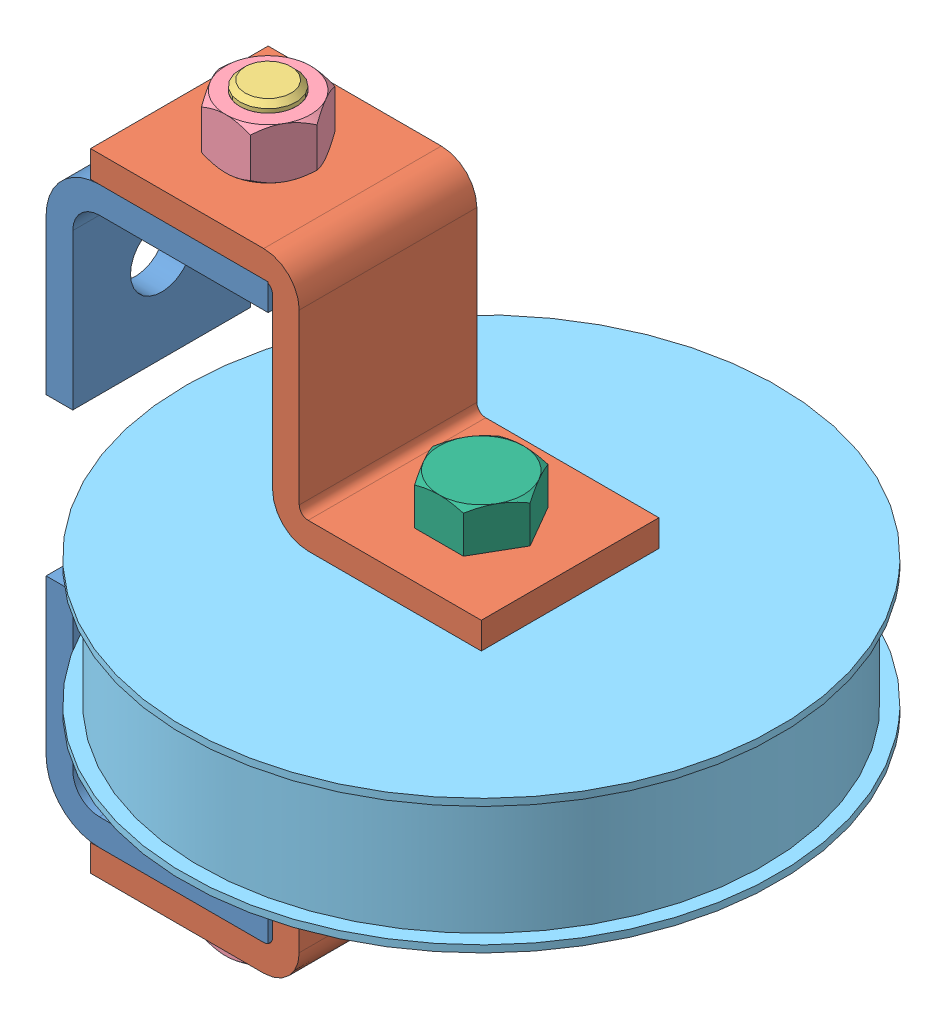
SolidWorks assembly Large Pulley Mount, configuration Default. Lengths in mm.
Overall size (187.97 168.14 187.97).
11 component instances, 6 part files, 17 mates.
Components (placement in the parent):
- P1026 - Unistrut 2-Hole 90 deg Fitting-1: P1026 - Unistrut 2-Hole 90 deg Fitting [Default] at (18.6827 -44.2712 5.2371) size (50 47 40)
- P1347 - Unistrut 2-Hole Z Fitting-1: P1347 - Unistrut 2-Hole Z Fitting [Default] at (28.6827 8.7288 -34.7629) x (1 0 0) z (0 0 -1) size (88 54 40)
- HBOLT 0.5000-13x1x1-N-1: HBOLT 0.5000-13x1x1-N [HBOLT 0.5000-13x1x1-N] at (48.6827 -12.5168 -14.7629) x (0 1 0) z (0 0 1) size (34.65 22 19.05)
- Hex Nut .5-20-2: Hex Nut .5-20 [HNUT 0.5000-20-D-N] at (48.6827 20.108 -14.7629) x (0.866025 0 -0.5) z (0 1 0) size (19.05 22 11.38)
- Wide Pulley-2: Wide Pulley [5"x0.5"] at (96.6827 -61.9399 -14.7629) x (0.762017 0 -0.647557) z (0 -1 0) size (133.35 133.35 30.16)
- Hex Bolt .5x3-2: Hex Bolt .5x3 [HBOLT 0.5000-20x3x3-N] at (96.6827 -30.0256 -14.7629) x (0 -1 0) z (0 0 1) size (85.45 22 19.05)
- P1026 - Unistrut 2-Hole 90 deg Fitting-2: P1026 - Unistrut 2-Hole 90 deg Fitting [Default] at (18.6827 -79.6087 -34.7629) x (1 0 0) z (0 0 -1) size (50 47 40)
- P1347 - Unistrut 2-Hole Z Fitting-2: P1347 - Unistrut 2-Hole Z Fitting [Default] at (28.6827 -132.6087 5.2371) size (88 54 40)
- HBOLT 0.5000-13x1x1-N-2: HBOLT 0.5000-13x1x1-N [HBOLT 0.5000-13x1x1-N] at (48.6827 -111.3631 -14.7629) x (0 -1 0) z (0 0 -1) size (34.65 22 19.05)
- Hex Nut .5-20-3: Hex Nut .5-20 [HNUT 0.5000-20-D-N] at (48.6827 -132.6087 -14.7629) x (0.866025 0 -0.5) z (0 1 0) size (19.05 22 11.38)
- Hex Nut .5-20-4: Hex Nut .5-20 [HNUT 0.5000-20-D-N] at (96.6827 -95.9879 -14.7629) x (0.866025 0 0.5) z (0 -1 0) size (19.05 22 11.38)
Mates (geometry in assembly coordinates):
- Concentric11: concentric aligned: cylinder of P1026 - Unistrut 2-Hole 90 deg Fitting-1 through (48.6827 -3.2712 -14.7629) axis (0 -1 0) radius 7; cylinder of HBOLT 0.5000-13x1x1-N-1 through (48.6827 -12.5168 -14.7629) axis (0 -1 0) radius 6.35
- Coincident21: coincident anti-aligned: plane of P1026 - Unistrut 2-Hole 90 deg Fitting-1 through (24.6827 -3.2712 5.2371) normal (0 -1 0); plane of HBOLT 0.5000-13x1x1-N-1 through (37.6841 -3.2712 -14.7629) normal (0 1 0)
- Concentric2: concentric anti-aligned: cylinder of P1347 - Unistrut 2-Hole Z Fitting-1 through (48.6827 8.7288 -14.7629) axis (0 1 0) radius 7; cylinder of HBOLT 0.5000-13x1x1-N-1 through (48.6827 -12.5168 -14.7629) axis (0 -1 0) radius 6.35
- Coincident5: coincident anti-aligned: plane of P1026 - Unistrut 2-Hole 90 deg Fitting-1 through (68.6827 2.7288 -34.7629) normal (0 1 0); plane of P1347 - Unistrut 2-Hole Z Fitting-1 through (28.6827 2.7288 5.2371) normal (0 -1 0)
- Parallel2: parallel aligned: plane of P1026 - Unistrut 2-Hole 90 deg Fitting-1 through (18.6827 2.7288 -34.7629) normal (-1 0 0); plane of P1347 - Unistrut 2-Hole Z Fitting-1 through (28.6827 8.7288 -34.7629) normal (-1 0 0)
- Concentric41: concentric anti-aligned: cylinder of HBOLT 0.5000-13x1x1-N-1 through (48.6827 -12.5168 -14.7629) axis (0 -1 0) radius 6.35; cylinder of Hex Nut .5-20-2 through (48.6827 -4.9295 -14.7629) axis (0 1 0) radius 6.35
- Coincident81: coincident anti-aligned: plane of P1347 - Unistrut 2-Hole Z Fitting-1 through (116.6827 8.7288 -34.7629) normal (0 1 0); plane of Hex Nut .5-20-2 through (32.1849 8.7288 -5.2379) normal (0 -1 0)
- Parallel3: parallel aligned: plane of HBOLT 0.5000-13x1x1-N-1 through (43.1834 -3.2712 -24.2879) normal (0 0 -1); plane of Hex Nut .5-20-2 through (54.1819 8.7288 -24.2879) normal (0 0 -1)
- Parallel4: parallel aligned: plane of P1026 - Unistrut 2-Hole 90 deg Fitting-1 through (18.6827 -44.2712 -34.7629) normal (0 0 -1); plane of HBOLT 0.5000-13x1x1-N-1 through (43.1834 -3.2712 -24.2879) normal (0 0 -1)
- Concentric51: concentric anti-aligned: cylinder of P1347 - Unistrut 2-Hole Z Fitting-1 through (96.6827 -45.2712 -14.7629) axis (0 -1 0) radius 7; cylinder of Hex Bolt .5x3-2 through (96.6827 -30.0256 -14.7629) axis (0 1 0) radius 6.35
- Coincident111: coincident anti-aligned: plane of P1347 - Unistrut 2-Hole Z Fitting-1 through (116.6827 -39.2712 5.2371) normal (0 1 0); plane of Hex Bolt .5x3-2 through (106.2077 -39.2712 -20.2622) normal (0 -1 0)
- Concentric6: concentric anti-aligned: cylinder of Wide Pulley-2 through (96.6827 -46.8587 -14.7629) axis (0 -1 0) radius 6.35; cylinder of Hex Bolt .5x3-2 through (96.6827 -30.0256 -14.7629) axis (0 1 0) radius 6.35
- Distance1: distance = 1.5875 mm anti-aligned: plane of Wide Pulley-2 through (96.6827 -46.8587 -14.7629) normal (0 1 0); plane of P1347 - Unistrut 2-Hole Z Fitting-1 through (28.6827 -45.2712 -34.7629) normal (0 -1 0)
- Concentric71: concentric anti-aligned: cylinder of ? through (96.6827 -70.9504 -14.7629) axis (0 -1 0) radius 6.35
- Coincident131: coincident anti-aligned: plane of P1347 - Unistrut 2-Hole Z Fitting-2 through (116.6827 -84.6087 -34.7629) normal (0 -1 0); plane of Hex Nut .5-20-4 through (77.6327 -84.6087 -14.7629) normal (0 1 0)
- Parallel5: parallel aligned: plane of Hex Bolt .5x3-2 through (102.1819 -39.2712 -24.2879) normal (0 0 -1); plane of Hex Nut .5-20-4 through (91.1834 -84.6087 -24.2879) normal (0 0 -1)
- Parallel6: parallel aligned: plane of P1347 - Unistrut 2-Hole Z Fitting-1 through (28.6827 8.7288 -34.7629) normal (0 0 -1); plane of Hex Bolt .5x3-2 through (102.1819 -39.2712 -24.2879) normal (0 0 -1)
